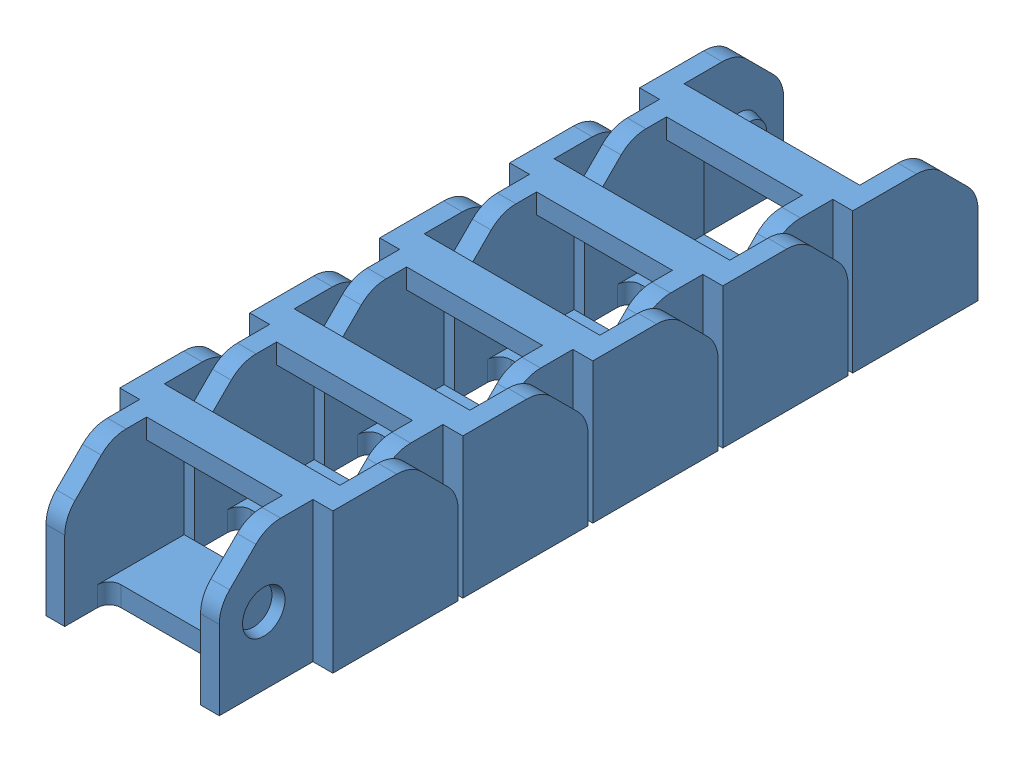
SolidWorks assembly PChain_5link, configuration Default. Lengths in mm.
Overall size (18.2 12 63.1).
5 component instances, 1 part files, 12 mates.
Components (placement in the parent):
- PChain_link-3: PChain_link [Default] at origin size (18.2 12 18.7)
- PChain_link-4: PChain_link [Default] at (0 0 11.1) size (18.2 12 18.7)
- PChain_link-5: PChain_link [Default] at (0 0 22.2) size (18.2 12 18.7)
- PChain_link-6: PChain_link [Default] at (0 0 33.3) size (18.2 12 18.7)
- PChain_link-18: PChain_link [Default] at (0 0 44.4) size (18.2 12 18.7)
Mates (geometry in assembly coordinates):
- Concentric1: concentric anti-aligned: circle of PChain_link-3; circle of PChain_link-4
- Coincident3: coincident aligned: plane of PChain_link-3 through (-9.1 12 -8.5) normal (-1 0 0); plane of PChain_link-4 through (-9.1 12 2.6) normal (-1 0 0)
- Concentric2: concentric aligned: circle of PChain_link-4; circle of PChain_link-5
- Coincident5: coincident aligned: plane of PChain_link-4 through (-9.1 12 2.6) normal (-1 0 0); plane of PChain_link-5 through (-9.1 12 13.7) normal (-1 0 0)
- Concentric3: concentric anti-aligned: circle of PChain_link-6; circle of PChain_link-18
- Coincident6: coincident aligned: plane of PChain_link-6 through (-9.1 12 24.8) normal (-1 0 0); plane of PChain_link-18 through (-9.1 12 35.9) normal (-1 0 0)
- Concentric4: concentric aligned: circle of PChain_link-5; circle of PChain_link-6
- Coincident7: coincident aligned: plane of PChain_link-5 through (-9.1 12 13.7) normal (-1 0 0); plane of PChain_link-6 through (-9.1 12 24.8) normal (-1 0 0)
- LimitAngle1: limit planar angle = 0 rad anti-aligned: plane of PChain_link-4 through (-7.5 12 2.6) normal (0 0 -1); plane of PChain_link-3 through (-9.1 12 2.2) normal (0 0 1)
- LimitAngle2: limit planar angle = 0 rad anti-aligned: plane of PChain_link-5 through (-7.5 12 13.7) normal (0 0 -1); plane of PChain_link-4 through (-9.1 12 13.3) normal (0 0 1)
- LimitAngle3: limit planar angle = 0 rad anti-aligned: plane of PChain_link-6 through (-7.5 12 24.8) normal (0 0 -1); plane of PChain_link-5 through (-9.1 12 24.4) normal (0 0 1)
- LimitAngle4: limit planar angle = 0 rad anti-aligned: plane of PChain_link-18 through (-7.5 12 35.9) normal (0 0 -1); plane of PChain_link-6 through (-9.1 12 35.5) normal (0 0 1)
